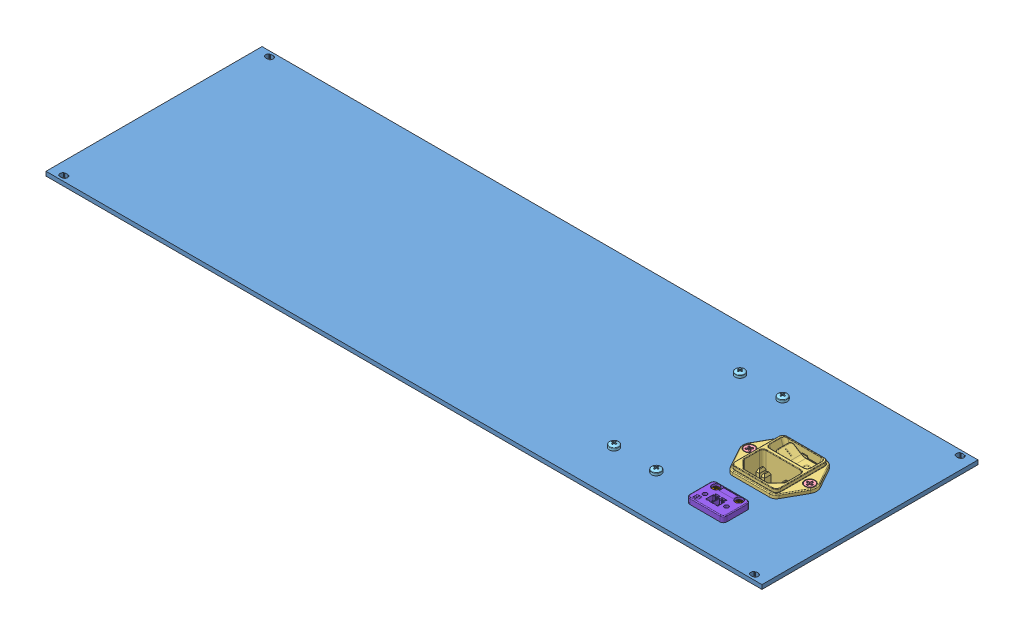
SolidWorks assembly MLA-0387-M9, configuration Default. Lengths in mm.
Overall size (426.52 36.95 128.7).
28 component instances, 11 part files, 51 mates.
Components (placement in the parent):
- MLA-0387-M8-1: MLA-0387-M8 [Default] at (14.077 -174.6299 585.4715) size (426.52 2.5 128.7)
- ECL15US12-S-1: ECL15US12-S [Default] at (340.987 202.9701 302.5215) x (0 0 -1) z (1 0 0) size (84 26.49 34.5)
- DC11_0001_001-1: DC11_0001_001 [Default] at (389.437 205.4701 308.5715) x (1 0 0) z (0 1 0) size (44 34 36.95)
- SCREW_ISO 7046-1: SCREW_ISO 7046 [VIJAK M 3x 10] at (371.437 207.6701 302.5215) x (0 -1 0) z (-0.609119 0 0.793079) size (10 5.6 5.6)
- SCREW_ISO 7046-2: SCREW_ISO 7046 [VIJAK M 3x 10] at (407.437 207.6701 302.5215) x (0 -1 0) z (0 0 1) size (10 5.6 5.6)
- M3 X 10mm Screw-1: M3 X 10mm Screw [Default] at (328.287 207.8701 340.0215) x (0 -1 0) z (0 0 1) size (12.61 5.6 5.6)
- M3 X 10mm Screw-2: M3 X 10mm Screw [Default] at (353.687 207.8701 340.2611) x (0 -1 0) z (0 0 1) size (12.61 5.6 5.6)
- M3 X 10mm Screw-3: M3 X 10mm Screw [Default] at (353.687 207.8701 265.0215) x (0 -1 0) z (0 0 1) size (12.61 5.6 5.6)
- M3 X 10mm Screw-4: M3 X 10mm Screw [Default] at (328.287 207.8701 265.0215) x (0 -1 0) z (0 0 1) size (12.61 5.6 5.6)
- M3 screw size FLAT WASHER-1: M3 screw size FLAT WASHER [Default] at (407.437 202.9701 302.5215) x (0.944963 0 -0.327176) z (0 -1 0) size (7 7 0.6)
- M3 screw size FLAT WASHER-2: M3 screw size FLAT WASHER [Default] at (371.437 202.3701 302.5215) x (1 0 0) z (0 1 0) size (7 7 0.6)
- M3 x 0.5mm Thread HEX NUT-1: M3 x 0.5mm Thread HEX NUT [Default] at (407.4348 201.1701 302.5562) x (1 0 0) z (0 1 0) size (5.5 6.35 2.6)
- M3 x 0.5mm Thread HEX NUT-2: M3 x 0.5mm Thread HEX NUT [Default] at (371.4463 201.1701 302.55) x (1 0 0) z (0 1 0) size (5.5 6.35 2.6)
- M3 screw size FLAT WASHER-3: M3 screw size FLAT WASHER [Default] at (353.687 199.8701 340.2611) x (1 0 0) z (0 1 0) size (7 7 0.6)
- M3 screw size FLAT WASHER-4: M3 screw size FLAT WASHER [Default] at (328.287 199.8701 340.0215) x (1 0 0) z (0 1 0) size (7 7 0.6)
- M3 screw size FLAT WASHER-5: M3 screw size FLAT WASHER [Default] at (328.287 200.4701 265.0215) x (1 0 0) z (0 -1 0) size (7 7 0.6)
- M3 screw size FLAT WASHER-6: M3 screw size FLAT WASHER [Default] at (353.687 200.4701 265.0215) x (1 0 0) z (0 -1 0) size (7 7 0.6)
- M3 x 0.5mm Thread HEX NUT-3: M3 x 0.5mm Thread HEX NUT [Default] at (328.3059 198.6701 265.0157) x (1 0 0) z (0 -1 0) size (5.5 6.35 2.6)
- M3 x 0.5mm Thread HEX NUT-4: M3 x 0.5mm Thread HEX NUT [Default] at (353.679 198.6701 264.9262) x (1 0 0) z (0 -1 0) size (5.5 6.35 2.6)
- M3 x 0.5mm Thread HEX NUT-5: M3 x 0.5mm Thread HEX NUT [Default] at (353.654 198.6701 340.285) x (1 0 0) z (0 1 0) size (5.5 6.35 2.6)
- M3 x 0.5mm Thread HEX NUT-6: M3 x 0.5mm Thread HEX NUT [Default] at (328.2745 198.6701 340.0301) x (1 0 0) z (0 1 0) size (5.5 6.35 2.6)
- 1829345_02-1: 1829345_02 [Default] at (387.527 203.3701 340.6215) x (0 1 0) z (-1 0 0) size (20.4 16.2 22.01)
- pan_head_phillip_mc_screw_m2-1: pan_head_phillip_mc_screw_m2 [Default] at (382.527 206.9701 333.6215) x (-0.384065 0 -0.923306) z (0.923306 0 -0.384065) size (4 9.78 4)
- pan_head_phillip_mc_screw_m2-2: pan_head_phillip_mc_screw_m2 [Default] at (396.337 206.9701 333.6215) x (0.556789 0 0.830654) z (-0.830654 0 0.556789) size (4 9.78 4)
- M2 washer-1: M2 washer [Default] at (396.337 202.6701 333.6215) size (5 0.3 5)
- M2 washer-2: M2 washer [Default] at (382.527 202.6701 333.6215) size (5 0.3 5)
- M2 Nut-1: M2 Nut [Default] at (396.337 201.0701 333.6215) x (1 0 0) z (0 -1 0) size (4 4.62 1.6)
- M2 Nut-2: M2 Nut [Default] at (382.527 201.0701 333.6215) x (1 0 0) z (0 -1 0) size (4 4.62 1.6)
Mates (geometry in assembly coordinates):
- Coincident1: coincident anti-aligned: plane of MLA-0387-M8-1 through (22.1573 202.9701 282.3956) normal (0 -1 0); plane of ECL15US12-S-1 through (358.237 202.9701 335.5215) normal (0 1 0)
- Distance1: distance = 22.35 mm aligned: line of ECL15US12-S-1 through (324.7368 202.9701 344.5215) axis (1 0 0); plane of MLA-0387-M8-1 through (443.237 202.9701 366.8715) normal (0 0 1)
- Coincident8: coincident anti-aligned: plane of MLA-0387-M8-1 through (22.1573 205.4701 282.3956) normal (0 1 0); plane of DC11_0001_001-1 through (378.437 205.4701 289.5215) normal (0 -1 0)
- Concentric2: concentric anti-aligned: cylinder of MLA-0387-M8-1 through (371.437 212.9701 302.5215) axis (0 -1 0) radius 1.8; cylinder of DC11_0001_001-1 through (371.437 207.6701 302.5215) axis (0 1 0) radius 1.6
- Concentric3: concentric anti-aligned: cylinder of MLA-0387-M8-1 through (407.437 212.9701 302.5215) axis (0 -1 0) radius 1.8; cylinder of DC11_0001_001-1 through (407.437 207.6701 302.5215) axis (0 1 0) radius 1.6
- Distance4: distance = 85 mm: line of MLA-0387-M8-1 through (443.237 202.9701 366.8715) axis (0 0 -1); line of ECL15US12-S-1 through (358.237 202.9701 343.5217) axis (0 0 -1)
- Concentric4: concentric aligned: cone of DC11_0001_001-1 through (371.437 207.4701 302.5215) axis (0 -1 0); cone of SCREW_ISO 7046-1 through (371.437 206.1701 302.5215) axis (0 -1 0)
- Coincident9: coincident aligned: plane of DC11_0001_001-1 through (378.437 207.6701 289.5215) normal (0 1 0); plane of SCREW_ISO 7046-1 through (371.437 207.6701 302.5215) normal (0 1 0)
- Concentric5: concentric aligned: cone of DC11_0001_001-1 through (407.437 207.4701 302.5215) axis (0 -1 0); cone of SCREW_ISO 7046-2 through (407.437 206.1701 302.5215) axis (0 -1 0)
- Coincident10: coincident aligned: plane of DC11_0001_001-1 through (378.437 207.6701 289.5215) normal (0 1 0); plane of SCREW_ISO 7046-2 through (407.437 207.6701 302.5215) normal (0 1 0)
- Coincident11: coincident anti-aligned: plane of MLA-0387-M8-1 through (22.1573 205.4701 282.3956) normal (0 1 0); plane of M3 X 10mm Screw-1 through (328.287 205.4701 338.5215) normal (0 -1 0)
- Concentric6: concentric aligned: cylinder of MLA-0387-M8-1 through (328.287 212.9701 340.0215) axis (0 -1 0) radius 1.8; cylinder of M3 X 10mm Screw-1 through (328.287 195.4701 340.0215) axis (0 -1 0) radius 2.8
- Coincident12: coincident anti-aligned: plane of MLA-0387-M8-1 through (22.1573 205.4701 282.3956) normal (0 1 0); plane of M3 X 10mm Screw-2 through (353.687 205.4701 338.7611) normal (0 -1 0)
- Concentric7: concentric aligned: cylinder of MLA-0387-M8-1 through (353.687 212.9701 340.2611) axis (0 -1 0) radius 1.8; cylinder of M3 X 10mm Screw-2 through (353.687 195.4701 340.2611) axis (0 -1 0) radius 2.8
- Coincident13: coincident anti-aligned: plane of MLA-0387-M8-1 through (22.1573 205.4701 282.3956) normal (0 1 0); plane of M3 X 10mm Screw-3 through (353.687 205.4701 263.5215) normal (0 -1 0)
- Concentric8: concentric aligned: cylinder of MLA-0387-M8-1 through (353.687 212.9701 265.0215) axis (0 -1 0) radius 1.8; cylinder of M3 X 10mm Screw-3 through (353.687 195.4701 265.0215) axis (0 -1 0) radius 2.8
- Coincident14: coincident anti-aligned: plane of MLA-0387-M8-1 through (22.1573 205.4701 282.3956) normal (0 1 0); plane of M3 X 10mm Screw-4 through (328.287 205.4701 263.5215) normal (0 -1 0)
- Concentric9: concentric aligned: cylinder of MLA-0387-M8-1 through (328.287 212.9701 265.0215) axis (0 -1 0) radius 1.8; cylinder of M3 X 10mm Screw-4 through (328.287 195.4701 265.0215) axis (0 -1 0) radius 2.8
- Coincident15: coincident anti-aligned: plane of MLA-0387-M8-1 through (22.1573 202.9701 282.3956) normal (0 -1 0); plane of M3 screw size FLAT WASHER-1 through (407.437 202.9701 302.5215) normal (0 1 0)
- Concentric10: concentric anti-aligned: cylinder of M3 screw size FLAT WASHER-1 through (407.437 202.3701 302.5215) axis (0 1 0) radius 1.6; cylinder of SCREW_ISO 7046-2 through (407.437 197.6701 302.5215) axis (0 -1 0) radius 2.8
- Coincident16: coincident anti-aligned: plane of MLA-0387-M8-1 through (22.1573 202.9701 282.3956) normal (0 -1 0); plane of M3 screw size FLAT WASHER-2 through (371.437 202.9701 302.5215) normal (0 1 0)
- Concentric11: concentric aligned: cylinder of MLA-0387-M8-1 through (371.437 212.9701 302.5215) axis (0 -1 0) radius 1.8; cylinder of M3 screw size FLAT WASHER-2 through (371.437 202.9701 302.5215) axis (0 -1 0) radius 1.6
- Coincident17: coincident anti-aligned: plane of M3 screw size FLAT WASHER-1 through (407.437 202.3701 302.5215) normal (0 -1 0); plane of M3 x 0.5mm Thread HEX NUT-1 through (404.6848 202.3701 300.9685) normal (0 1 0)
- Coincident18: coincident anti-aligned: plane of M3 screw size FLAT WASHER-2 through (371.437 202.3701 302.5215) normal (0 -1 0); plane of M3 x 0.5mm Thread HEX NUT-2 through (368.6963 202.3701 300.9623) normal (0 1 0)
- Coincident19: coincident anti-aligned: plane of ECL15US12-S-1 through (358.237 200.4701 335.0215) normal (0 -1 0); plane of M3 screw size FLAT WASHER-3 through (353.687 200.4701 340.2611) normal (0 1 0)
- Concentric13: concentric aligned: cylinder of M3 X 10mm Screw-2 through (353.687 195.4701 340.2611) axis (0 -1 0) radius 2.8; cylinder of M3 screw size FLAT WASHER-3 through (353.687 200.4701 340.2611) axis (0 -1 0) radius 3.5
- Coincident20: coincident anti-aligned: plane of ECL15US12-S-1 through (358.237 200.4701 335.0215) normal (0 -1 0); plane of M3 screw size FLAT WASHER-4 through (328.287 200.4701 340.0215) normal (0 1 0)
- Concentric14: concentric aligned: cylinder of M3 X 10mm Screw-1 through (328.287 195.4701 340.0215) axis (0 -1 0) radius 2.8; cylinder of M3 screw size FLAT WASHER-4 through (328.287 200.4701 340.0215) axis (0 -1 0) radius 3.5
- Coincident21: coincident anti-aligned: plane of ECL15US12-S-1 through (358.237 200.4701 270.0215) normal (0 -1 0); plane of M3 screw size FLAT WASHER-5 through (328.287 200.4701 265.0215) normal (0 1 0)
- Concentric15: concentric aligned: cylinder of M3 X 10mm Screw-4 through (328.287 195.4701 265.0215) axis (0 -1 0) radius 2.8; circle of M3 screw size FLAT WASHER-5
- Coincident22: coincident anti-aligned: plane of ECL15US12-S-1 through (358.237 200.4701 270.0215) normal (0 -1 0); plane of M3 screw size FLAT WASHER-6 through (353.687 200.4701 265.0215) normal (0 1 0)
- Concentric16: concentric anti-aligned: circle of M3 X 10mm Screw-3; cylinder of M3 screw size FLAT WASHER-6 through (353.687 199.8701 265.0215) axis (0 1 0) radius 3.5
- Coincident24: coincident anti-aligned: plane of M3 screw size FLAT WASHER-5 through (328.287 199.8701 265.0215) normal (0 -1 0); plane of M3 x 0.5mm Thread HEX NUT-3 through (325.5559 199.8701 266.6034) normal (0 1 0)
- Coincident25: coincident anti-aligned: plane of M3 screw size FLAT WASHER-6 through (353.687 199.8701 265.0215) normal (0 -1 0); plane of M3 x 0.5mm Thread HEX NUT-4 through (350.929 199.8701 266.5139) normal (0 1 0)
- Coincident26: coincident anti-aligned: plane of M3 screw size FLAT WASHER-3 through (353.687 199.8701 340.2611) normal (0 -1 0); plane of M3 x 0.5mm Thread HEX NUT-5 through (350.904 199.8701 338.6973) normal (0 1 0)
- Coincident27: coincident anti-aligned: plane of M3 screw size FLAT WASHER-4 through (328.287 199.8701 340.0215) normal (0 -1 0); plane of M3 x 0.5mm Thread HEX NUT-6 through (325.5245 199.8701 338.4424) normal (0 1 0)
- Concentric17: concentric anti-aligned: cylinder of MLA-0387-M8-1 through (382.527 212.9701 333.6215) axis (0 -1 0) radius 1.15; cylinder of 1829345_02-1 through (382.527 196.8661 333.6215) axis (0 1 0) radius 1.15
- Concentric18: concentric anti-aligned: cylinder of MLA-0387-M8-1 through (396.337 212.9701 333.6215) axis (0 -1 0) radius 1.15; cylinder of 1829345_02-1 through (396.337 196.8661 333.6215) axis (0 1 0) radius 1.15
- Coincident32: coincident anti-aligned: plane of MLA-0387-M8-1 through (22.1573 205.4701 282.3956) normal (0 1 0); plane of 1829345_02-1 through (380.432 205.4701 348.6415) normal (0 -1 0)
- Concentric19: concentric anti-aligned: cylinder of 1829345_02-1 through (382.527 196.8661 333.6215) axis (0 1 0) radius 1.15; cylinder of pan_head_phillip_mc_screw_m2-1 through (382.527 208.7551 333.6215) axis (0 -1 0) radius 2
- Coincident33: coincident anti-aligned: plane of 1829345_02-1 through (388.0071 206.9701 335.7282) normal (0 1 0); plane of pan_head_phillip_mc_screw_m2-1 through (382.527 206.9701 333.6215) normal (0 -1 0)
- Concentric20: concentric anti-aligned: cylinder of 1829345_02-1 through (396.337 196.8661 333.6215) axis (0 1 0) radius 1.15; circle of pan_head_phillip_mc_screw_m2-2
- Coincident34: coincident anti-aligned: plane of 1829345_02-1 through (388.0071 206.9701 335.7282) normal (0 1 0); plane of pan_head_phillip_mc_screw_m2-2 through (396.337 206.9701 333.6215) normal (0 -1 0)
- Coincident35: coincident anti-aligned: plane of MLA-0387-M8-1 through (22.1573 202.9701 282.3956) normal (0 -1 0); plane of M2 washer-1 through (396.337 202.9701 333.6215) normal (0 1 0)
- Concentric22: concentric anti-aligned: cylinder of MLA-0387-M8-1 through (396.337 212.9701 333.6215) axis (0 -1 0) radius 1.15; cylinder of M2 washer-1 through (396.337 202.6701 333.6215) axis (0 1 0) radius 1.1
- Coincident36: coincident anti-aligned: plane of MLA-0387-M8-1 through (22.1573 202.9701 282.3956) normal (0 -1 0); plane of M2 washer-2 through (382.527 202.9701 333.6215) normal (0 1 0)
- Concentric23: concentric anti-aligned: cylinder of MLA-0387-M8-1 through (382.527 212.9701 333.6215) axis (0 -1 0) radius 1.15; cylinder of M2 washer-2 through (382.527 202.6701 333.6215) axis (0 1 0) radius 1.1
- Coincident37: coincident: plane of M2 washer-1 through (396.337 202.6701 333.6215) normal (0 -1 0); plane of M2 Nut-1 through (400.837 202.6701 335.1747) normal (0 1 0)
- Concentric25: concentric anti-aligned: circle of M2 washer-1; circle of M2 Nut-1
- Coincident38: coincident anti-aligned: plane of M2 washer-2 through (382.527 202.6701 333.6215) normal (0 -1 0); plane of M2 Nut-2 through (382.527 202.6701 335.9309) normal (0 1 0)
- Concentric26: concentric aligned: cylinder of MLA-0387-M8-1 through (382.527 212.9701 333.6215) axis (0 -1 0) radius 1.15; circle of M2 Nut-2
